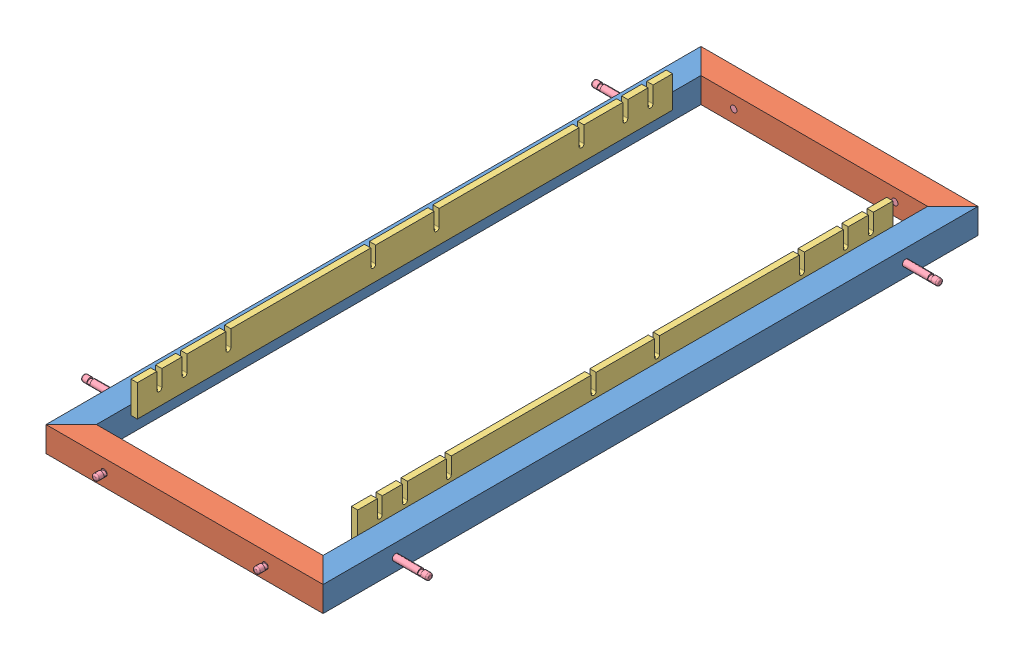
SolidWorks assembly 900-Frame, configuration Default. Lengths in mm.
Overall size (698.5 95.25 1358.9).
14 component instances, 4 part files, 15 mates.
Components (placement in the parent):
- 309-TubingSquareTop-1: 309-TubingSquareTop [Default] at origin size (50.8 50.8 1320.8)
- 304-BarUpper-1: 304-BarUpper [Default] at (-91.6 1473.2 457.2) x (0 -1 0) z (1 0 0) size (50.8 50.8 558.8)
- 307-HoldingBarRods-1: 307-HoldingBarRods [Default] at (-215.9 0 0) x (0 0 1) z (-1 0 0) size (1079.5 63.5 12.7)
- 321-DowellGrooved-1: 321-DowellGrooved [long] at (799.775 1068.7589 -654.05) x (0 1 0) z (0 0 1) size (12.7 12.7 69.85)
- 321-DowellGrooved-2: 321-DowellGrooved [extralong] at (-323.85 1068.7589 -1476.525) x (0 1 0) z (1 0 0) size (12.7 12.7 120.65)
- 321-DowellGrooved-3: 321-DowellGrooved [extralong] at (-323.85 1068.7589 -447.825) x (0 1 0) z (1 0 0) size (12.7 12.7 120.65)
- 309-TubingSquareTop-2: 309-TubingSquareTop [Default] x (-1 0 0) z (0 0 -1) size (50.8 50.8 1320.8)
- 307-HoldingBarRods-2: 307-HoldingBarRods [Default] at (228.6 0 0) x (0 0 1) z (-1 0 0) size (1079.5 63.5 12.7)
- 321-DowellGrooved-4: 321-DowellGrooved [long] at (1124.575 1068.7589 -654.05) x (0 1 0) z (0 0 1) size (12.7 12.7 69.85)
- 321-DowellGrooved-5: 321-DowellGrooved [extralong] at (323.85 1068.7589 447.825) x (0 1 0) z (-1 0 0) size (12.7 12.7 120.65)
- 321-DowellGrooved-6: 321-DowellGrooved [extralong] at (323.85 1068.7589 1476.525) x (0 1 0) z (-1 0 0) size (12.7 12.7 120.65)
- 304-BarUpper-2: 304-BarUpper [Default] at (91.6 1473.2 -457.2) x (0 -1 0) z (-1 0 0) size (50.8 50.8 558.8)
- 321-DowellGrooved-7: 321-DowellGrooved [long] at (-1124.575 1068.7589 654.05) x (0 1 0) z (0 0 -1) size (12.7 12.7 69.85)
- 321-DowellGrooved-8: 321-DowellGrooved [long] at (-799.775 1068.7589 654.05) x (0 1 0) z (0 0 -1) size (12.7 12.7 69.85)
Mates (geometry in assembly coordinates):
- Coincident2: coincident anti-aligned: line of 309-TubingSquareTop-1; line of 304-BarUpper-1
- Coincident4: coincident aligned: plane of 309-TubingSquareTop-1 through (-279.4 933.45 660.4) normal (0 -1 0); plane of 304-BarUpper-1 through (279.4 933.45 -660.4) normal (0 -1 0)
- Coincident5: coincident anti-aligned: line of 309-TubingSquareTop-1; line of 304-BarUpper-1
- Coincident6: coincident anti-aligned: plane of 309-TubingSquareTop-1 through (-228.6 984.25 660.4) normal (1 0 0); plane of 307-HoldingBarRods-1 through (-228.6 965.2 -539.75) normal (-1 0 0)
- Coincident7: coincident aligned: plane of 309-TubingSquareTop-1 through (0 0 0) normal (0 0 1); plane of 307-HoldingBarRods-1 through (-215.9 0 0) normal (0 0 1)
- Distance1: distance = 31.75 mm aligned: plane of 309-TubingSquareTop-1 through (-279.4 933.45 660.4) normal (0 -1 0); plane of 307-HoldingBarRods-1 through (-228.6 965.2 -539.75) normal (0 -1 0)
- Concentric1: concentric anti-aligned: cylinder of 304-BarUpper-1
- Coincident9: coincident aligned: unknown of 304-BarUpper-1
- Parallel1: parallel anti-aligned: unknown of 304-BarUpper-1
- Concentric2: concentric anti-aligned: unknown of 309-TubingSquareTop-1
- Parallel2: parallel aligned: unknown of 309-TubingSquareTop-1
- Coincident14: coincident aligned: unknown of 309-TubingSquareTop-1
- Coincident15: coincident aligned: unknown of 309-TubingSquareTop-1
- Coincident16: coincident aligned: unknown of 309-TubingSquareTop-2
- Coincident17: coincident aligned: unknown of 309-TubingSquareTop-2
